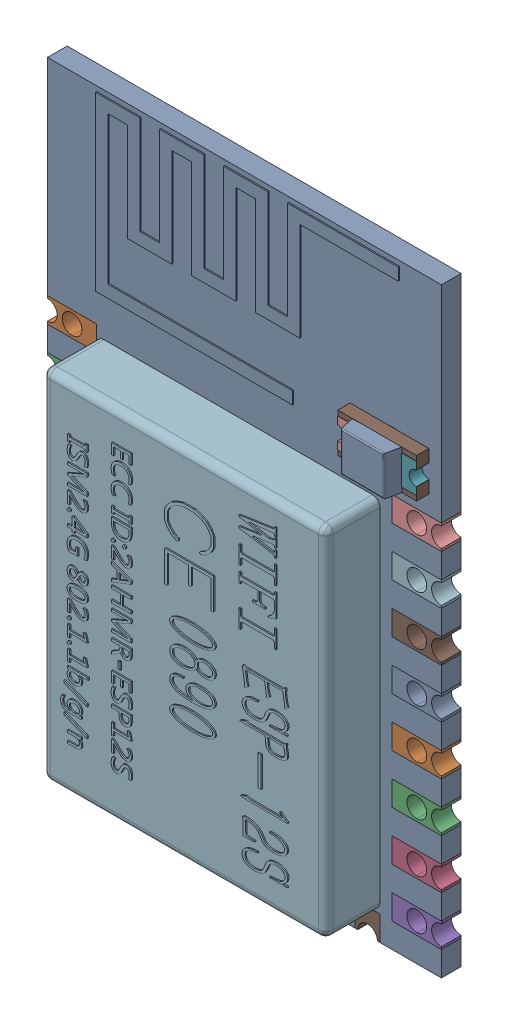
SolidWorks assembly P3, configuration 默认. Lengths in mm.
Overall size (16 24.38 3.05).
27 component instances, 6 part files, 0 mates.
Components (placement in the parent):
- 0411-2-1: 0411-2 [默认] at (11.34 12.4403 0) x (0 1 0) z (-1 0 0) size (24.38 3.05 16)
  - User_Library-ESP8266-12E_PCB1-1: User_Library-ESP8266-12E_PCB1 [默认] x (-1 0 0) z (0 0 1) size (24.38 0.8 16)
  - User_Library-ESP8266-12E_Pin1-1: User_Library-ESP8266-12E_Pin1 [默认] at (3.31 0 8) x (-1 0 0) z (0 -1 0) size (1 2 0.8)
  - User_Library-ESP8266-12E_Pin1-2: User_Library-ESP8266-12E_Pin1 [默认] at (1.31 0 8) x (-1 0 0) z (0 -1 0) size (1 2 0.8)
  - User_Library-ESP8266-12E_Pin1-3: User_Library-ESP8266-12E_Pin1 [默认] at (-0.69 0 8) x (-1 0 0) z (0 -1 0) size (1 2 0.8)
  - User_Library-ESP8266-12E_Pin1-4: User_Library-ESP8266-12E_Pin1 [默认] at (-2.69 0 8) x (-1 0 0) z (0 -1 0) size (1 2 0.8)
  - User_Library-ESP8266-12E_Pin1-5: User_Library-ESP8266-12E_Pin1 [默认] at (-4.69 0 8) x (-1 0 0) z (0 -1 0) size (1 2 0.8)
  - User_Library-ESP8266-12E_Pin1-6: User_Library-ESP8266-12E_Pin1 [默认] at (-6.69 0 8) x (-1 0 0) z (0 -1 0) size (1 2 0.8)
  - User_Library-ESP8266-12E_Pin1-7: User_Library-ESP8266-12E_Pin1 [默认] at (-8.69 0 8) x (-1 0 0) z (0 -1 0) size (1 2 0.8)
  - User_Library-ESP8266-12E_Pin1-8: User_Library-ESP8266-12E_Pin1 [默认] at (-10.69 0 8) x (-1 0 0) z (0 -1 0) size (1 2 0.8)
  - User_Library-ESP8266-12E_Pin1-9: User_Library-ESP8266-12E_Pin1 [默认] at (3.31 0 -8) x (1 0 0) z (0 -1 0) size (1 2 0.8)
  - User_Library-ESP8266-12E_Pin1-10: User_Library-ESP8266-12E_Pin1 [默认] at (-0.69 0 -8) x (1 0 0) z (0 -1 0) size (1 2 0.8)
  - User_Library-ESP8266-12E_Pin1-11: User_Library-ESP8266-12E_Pin1 [默认] at (1.31 0 -8) x (1 0 0) z (0 -1 0) size (1 2 0.8)
  - User_Library-ESP8266-12E_Pin1-12: User_Library-ESP8266-12E_Pin1 [默认] at (-2.69 0 -8) x (1 0 0) z (0 -1 0) size (1 2 0.8)
  - User_Library-ESP8266-12E_Pin1-13: User_Library-ESP8266-12E_Pin1 [默认] at (-4.69 0 -8) x (1 0 0) z (0 -1 0) size (1 2 0.8)
  - User_Library-ESP8266-12E_Pin1-14: User_Library-ESP8266-12E_Pin1 [默认] at (-6.69 0 -8) x (1 0 0) z (0 -1 0) size (1 2 0.8)
  - User_Library-ESP8266-12E_Pin1-15: User_Library-ESP8266-12E_Pin1 [默认] at (-8.69 0 -8) x (1 0 0) z (0 -1 0) size (1 2 0.8)
  - User_Library-ESP8266-12E_Pin1-16: User_Library-ESP8266-12E_Pin1 [默认] at (-10.69 0 -8) x (1 0 0) z (0 -1 0) size (1 2 0.8)
  - User_Library-ESP8266-12E_Pin2-1: User_Library-ESP8266-12E_Pin2 [默认] at (-12.19 0 5) x (0 0 1) z (0 1 0) size (1 1 0.8)
  - User_Library-ESP8266-12E_Pin2-2: User_Library-ESP8266-12E_Pin2 [默认] at (-12.19 0 3) x (0 0 -1) z (0 -1 0) size (1 1 0.8)
  - User_Library-ESP8266-12E_Pin2-3: User_Library-ESP8266-12E_Pin2 [默认] at (-12.19 0 1) x (0 0 1) z (0 1 0) size (1 1 0.8)
  - User_Library-ESP8266-12E_Pin2-4: User_Library-ESP8266-12E_Pin2 [默认] at (-12.19 0 -1) x (0 0 1) z (0 1 0) size (1 1 0.8)
  - User_Library-ESP8266-12E_Pin2-5: User_Library-ESP8266-12E_Pin2 [默认] at (-12.19 0 -3) x (0 0 1) z (0 1 0) size (1 1 0.8)
  - User_Library-ESP8266-12E_Pin2-6: User_Library-ESP8266-12E_Pin2 [默认] at (-12.19 0 -5) x (0 0 1) z (0 1 0) size (1 1 0.8)
  - User_Library-ESP8266-12E_Lid-1: User_Library-ESP8266-12E_Lid [默认] at (-3.84 -1.5 0.25) x (0 0 -1) z (0 -1 0) size (11.5 14.5 2.25)
  - User_Library-ESP8266-12E_Antenne-1: User_Library-ESP8266-12E_Antenne [默认] at (4.99 -0.425 6) x (0 0 -1) z (0 -1 0) size (12.3 7 0.05)
  - User_Library-ESP8266-12E_Surface_Mount_Chip_LED_3.2x1.6mm-1: User_Library-ESP8266-12E_Surface_Mount_Chip_LED_3.2x1.6mm [默认] at (6.19 -0.41 -7.5) x (0 0 1) z (0 -1 0) size (3.2 1.6 1.13)
